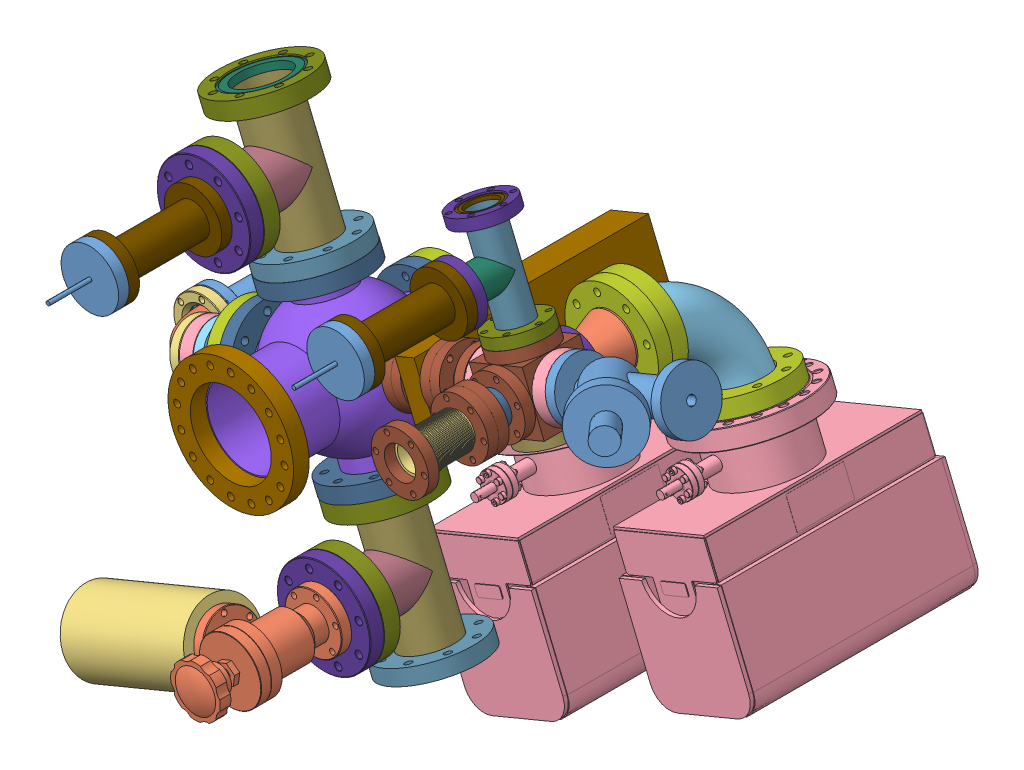
SolidWorks assembly Oven_BEC5, configuration Default. Lengths in mm.
Overall size (703.38 642.32 644.93).
104 component instances, 40 part files, 83 mates.
Components (placement in the parent):
- mdc 275 halfnipple-1: mdc 275 halfnipple [Default] at (-24.8274 -18.3346 25.5574) size (69.34 69.34 62.48)
- L275-403502-6: L275-403502 [Default] at (27.1869 1.5159 24.2874) x (-0.923728 -0.383049 0) z (0 0 -1) size (77.27 39.99 77.27)
- 915002-3: 915002 [Default] at (-24.8274 -18.3346 38.2574) x (0 0 -1) z (1 0 0) size (12.7 69.34 69.34)
- mdc 2.75 doublesided_hole-1: mdc 2.75 doublesided_hole [Default] at (43.4775 8.648 79.5644) x (0.146727 -0.353833 -0.923728) z (0.923728 0.383049 0) size (69.34 69.34 19.05)
- 915002-4: 915002 [Default] at (14.1491 -3.5138 79.5644) x (0.923728 0.383049 0) z (0 0 1) size (12.7 69.34 69.34)
- 100014 (2.75 X 1.5 REC)-1: 100014 (2.75 X 1.5 REC) [Default] at (43.4775 8.648 79.5644) x (0.923728 0.383049 0) z (0 0 1) size (12.7 69.34 69.34)
- red1-402032-001-1: red1-402032-001 [Default] at (97.817 31.1814 79.5644) x (-0.923728 -0.383049 0) z (0 0 1) size (60.1 63.5 63.5)
- 110021 (4.5 X 2.5 NR)-1: 110021 (4.5 X 2.5 NR) [Default] at (97.817 31.1814 79.5644) x (-0.923728 -0.383049 0) z (0 0 1) size (17.27 113.54 113.54)
- custom_sixway_cross-1: custom_sixway_cross [Default] at (189.7246 79.077 65.1716) x (-0.923728 -0.383049 0) z (-0.383049 0.923728 0) size (201.17 247.4 209.3)
  - custom_sixway_tube-1: custom_sixway_tube [Default] at (-1.4041 14.3928 -9.0374) size (170.94 210.82 174.24)
  - 6in_CF_flange-3: 6in_CF_flange [Default] at (-1.4041 157.1408 -9.0374) x (1 0 0) z (0 -1 0) size (152.4 152.4 19.05)
  - 4.5in_CF_flange-1: 4.5in_CF_flange [Default] at (85.7179 14.3928 -9.0374) x (0 -1 0) z (0 0 1) size (114.3 17.53 114.3)
  - 4.5in_CF_flange-2: 4.5in_CF_flange [Default] at (-1.4041 14.3928 78.0846) x (1 0 0) z (0 -1 0) size (114.3 17.53 114.3)
  - 4.5in_CF_flange-3: 4.5in_CF_flange [Default] at (-1.4041 14.3928 -113.6854) x (1 0 0) z (0 -1 0) size (114.3 17.53 114.3)
  - 2.75in_CF_flange-1: 2.75in_CF_flange [Default] at (-97.9241 14.3928 -9.0374) x (0 -1 0) z (0 0 1) size (69.85 12.7 69.85)
  - 4.5in_CF_flange-4: 4.5in_CF_flange [Default] at (-1.4041 -90.2552 -9.0374) size (114.3 17.53 114.3)
- T4-404038-1: T4-404038 [Default] at (92.3728 317.5077 79.5644) x (0.923728 0.383049 0) z (0.383049 -0.923728 0) size (113.54 142.49 171.45)
  - 404038-001-1: 404038-001 [Default] at origin size (63.51 63.51 152.4)
  - 404038-002-1: 404038-002 [Default] at (0 0 76.2) x (1 0 0) z (0 1 0) size (63.5 63.5 78.71)
  - 110021 (4.5 X 2.5 NR)_1-1: 110021 (4.5 X 2.5 NR)_1 [Default] at (0 0 161.925) x (0 0 -1) z (1 0 0) size (17.27 113.54 113.54)
  - 100021 (4.5 X 2.5 R)_1-1: 100021 (4.5 X 2.5 R)_1 [Default] at (0 73.025 76.2) x (0 1 0) z (0 0 1) size (19.05 113.54 113.54)
    - 100021 (4.5 X 2.5 INS)_1-1: 100021 (4.5 X 2.5 INS)_1 [Default] at origin size (12.04 82.3 82.3)
    - 100021 (4.5 X 2.5 REC)_1-1: 100021 (4.5 X 2.5 REC)_1 [Default] at (-6.35 0 0) x (1 0 0) z (0 0 -1) size (19.05 113.54 113.54)
  - 100021 (4.5 X 2.5 R)_1-2: 100021 (4.5 X 2.5 R)_1 [Default] at (0 0 3.175) x (0 0 -1) z (1 0 0) size (19.05 113.54 113.54)
    - 100021 (4.5 X 2.5 INS)_1-1: 100021 (4.5 X 2.5 INS)_1 [Default] at origin size (12.04 82.3 82.3)
    - 100021 (4.5 X 2.5 REC)_1-1: 100021 (4.5 X 2.5 REC)_1 [Default] at (-6.35 0 0) x (1 0 0) z (0 0 -1) size (19.05 113.54 113.54)
- zerolength 2.75 to 4.5 mdc-1: zerolength 2.75 to 4.5 mdc [Default] at (121.5611 247.1196 165.2894) x (-0.923728 -0.383049 0) z (0 0 -1) size (113.54 113.54 17.27)
- nipple 2.75 mdc-1: nipple 2.75 mdc [Default] at (121.5611 247.1196 307.7834) x (1 0 0) z (0 1 0) size (69.85 125.22 69.85)
- ion gauge uhv 24p footprint-1: ion gauge uhv 24p footprint [Default] at (121.5611 247.1196 320.4834) x (1 0 0) z (0 1 0) size (69.85 147.62 69.85)
- angle valve 1.5 inch 310029 mdc-1: angle valve 1.5 inch 310029 mdc [Default] at (267.4055 -104.5861 283.2724) x (-0.923728 -0.383049 0) z (-0.383049 0.923728 0) size (100.2 160.92 75.44)
- T4-404038-2: T4-404038 [Default] at (238.2172 -34.1981 79.5644) x (0.923728 0.383049 0) z (0.383049 -0.923728 0) size (113.54 142.49 171.45)
  - 404038-001-1: 404038-001 [Default] at origin size (63.51 63.51 152.4)
  - 404038-002-1: 404038-002 [Default] at (0 0 76.2) x (1 0 0) z (0 1 0) size (63.5 63.5 78.71)
  - 110021 (4.5 X 2.5 NR)_1-1: 110021 (4.5 X 2.5 NR)_1 [Default] at (0 0 161.925) x (0 0 -1) z (1 0 0) size (17.27 113.54 113.54)
  - 100021 (4.5 X 2.5 R)_1-1: 100021 (4.5 X 2.5 R)_1 [Default] at (0 73.025 76.2) x (0 1 0) z (0 0 1) size (19.05 113.54 113.54)
    - 100021 (4.5 X 2.5 INS)_1-1: 100021 (4.5 X 2.5 INS)_1 [Default] at origin size (12.04 82.3 82.3)
    - 100021 (4.5 X 2.5 REC)_1-1: 100021 (4.5 X 2.5 REC)_1 [Default] at (-6.35 0 0) x (1 0 0) z (0 0 -1) size (19.05 113.54 113.54)
  - 100021 (4.5 X 2.5 R)_1-2: 100021 (4.5 X 2.5 R)_1 [Default] at (0 0 3.175) x (0 0 -1) z (1 0 0) size (19.05 113.54 113.54)
    - 100021 (4.5 X 2.5 INS)_1-1: 100021 (4.5 X 2.5 INS)_1 [Default] at origin size (12.04 82.3 82.3)
    - 100021 (4.5 X 2.5 REC)_1-1: 100021 (4.5 X 2.5 REC)_1 [Default] at (-6.35 0 0) x (1 0 0) z (0 0 -1) size (19.05 113.54 113.54)
- zerolength 2.75 to 4.5 mdc-3: zerolength 2.75 to 4.5 mdc [Default] at (267.4055 -104.5861 165.2894) x (-0.923728 -0.383049 0) z (0 0 -1) size (113.54 113.54 17.27)
- turbo pump footpring-1: turbo pump footpring [Default] at (209.6873 -128.5206 245.9852) x (-0.383049 0.923728 0) z (0 0 1) size (91.44 162.05 91.44)
- ion pump gamma vacuum 75S-6S-KG_SW0003-1: ion pump gamma vacuum 75S-6S-KG_SW0003 [Default] at (324.7489 -242.8704 -129.9856) x (0.923728 0.383049 0) z (0 0 1) size (151.64 242.24 276.78)
- L4-403004_1-3: L4-403004_1 [Default] at (231.0174 -16.8357 -129.9856) x (0 0 1) z (-0.923728 -0.383049 0) size (161.67 161.67 113.54)
  - 403004-001_1-1: 403004-001_1 [Default] at origin size (128.92 128.92 67.08)
  - 100021 (4.5 X 2.5 R)_2-1: 100021 (4.5 X 2.5 R)_2 [Default] at (92.202 95.377 0) x (1 0 0) z (0 0 -1) size (19.05 113.54 113.54)
    - 100021 (4.5 X 2.5 INS)_2-1: 100021 (4.5 X 2.5 INS)_2 [Default] at origin size (12.04 82.3 82.3)
    - 100021 (4.5 X 2.5 REC)_2-1: 100021 (4.5 X 2.5 REC)_2 [Default] at (-6.35 0 0) x (1 0 0) z (0 0 -1) size (19.05 113.54 113.54)
  - 100021 (4.5 X 2.5 R)_2-2: 100021 (4.5 X 2.5 R)_2 [Default] at (0 3.175 0) x (0 -1 0) z (0 0 -1) size (19.05 113.54 113.54)
    - 100021 (4.5 X 2.5 INS)_2-1: 100021 (4.5 X 2.5 INS)_2 [Default] at origin size (12.04 82.3 82.3)
    - 100021 (4.5 X 2.5 REC)_2-1: 100021 (4.5 X 2.5 REC)_2 [Default] at (-6.35 0 0) x (1 0 0) z (0 0 -1) size (19.05 113.54 113.54)
- zerolength 6 45 mdc-1: zerolength 6 45 mdc [Default] at (242.2549 -43.9351 -129.9856) x (0.853273 0.353833 -0.383049) z (0.383049 -0.923728 0) size (151.64 151.64 19.81)
- gatevalve-1: gatevalve [Default] at (298.9549 11.514 55.3656) x (0.383049 -0.923728 0) z (0.923728 0.383049 0) size (88.9 280.54 50.84)
  - gatevalve_body-1: gatevalve_body [Default] at (-95.213 2.8522 48.3049) size (88.9 277.88 50.04)
  - 2.75in_CF_flange-3: 2.75in_CF_flange [Default] at (-95.213 -24.1988 73.7492) x (1 0 0) z (0 1 0) size (69.85 12.7 69.85)
  - 2.75in_CF_flange-4: 2.75in_CF_flange [Default] at (-95.213 -24.1988 35.6049) x (-1 0 0) z (0 -1 0) size (69.85 12.7 69.85)
- minilength_nipple-1: minilength_nipple [Default] at (349.6703 127.2966 78.7528) x (0.383049 -0.923728 0) z (0 0 1) size (69.85 44.45 69.85)
  - minilength_nipple_tube-1: minilength_nipple_tube [Default] at (-7.6879 4.7765 0.8117) size (38.1 19.05 38.1)
  - 2.75in_CF_flange-3: 2.75in_CF_flange [Default] at (-7.6879 14.3015 0.8117) size (69.85 12.7 69.85)
  - 2.75in_CF_flange-4: 2.75in_CF_flange [Default] at (-7.6879 -17.4485 0.8117) size (69.85 12.7 69.85)
- mdc 2.75 doublesided_hole-4: mdc 2.75 doublesided_hole [Default] at (371.6676 144.741 79.5644) x (0.146727 -0.353833 0.923728) z (-0.923728 -0.383049 0) size (69.34 69.34 19.05)
- mdc 2.75 doublesided_hole-5: mdc 2.75 doublesided_hole [Default] at (453.787 178.7941 79.5644) x (0.146727 -0.353833 0.923728) z (-0.923728 -0.383049 0) size (69.34 69.34 19.05)
- six way cube-1: six way cube [Default] at (421.5258 165.4161 79.5644) x (0 0 1) z (-0.923728 -0.383049 0) size (69.85 69.85 69.85)
- 2.75in  window mdc-1: 2.75in  window mdc [Default] at (439.7685 121.4235 79.5644) x (0.853273 0.353833 0.383049) z (-0.383049 0.923728 0) size (69.34 69.34 12.7)
  - Part3^2.75in  window mdc-1: Part3^2.75in  window mdc [Default] at origin size (69.34 69.34 12.7) (virtual)
  - Part4^2.75in  window mdc-1: Part4^2.75in  window mdc [Default] at (0 0 12.7) size (38.1 38.1 2.67) (virtual)
- T275-404002_a-1: T275-404002_a [Default] at (357.4671 319.8944 79.5644) x (0.923728 0.383049 0) z (0.383049 -0.923728 0) size (69.34 97.13 124.92)
  - 404002-001-1: 404002-001 [Default] at origin size (38.1 38.1 114.3)
  - 404002-002-1: 404002-002 [Default] at (0 0 57.15) x (-1 0 0) z (0 1 0) size (38.1 38.1 58.53)
  - 110014 (2.75 X 1.5 NR)_1-1: 110014 (2.75 X 1.5 NR)_1 [Default] at (0 0 113.2586) x (0 0 1) z (-1 0 0) size (12.7 69.34 69.34)
  - 100014 (2.75 X 1.5 R)-1: 100014 (2.75 X 1.5 R) [Default] at (0 62.4586 57.15) x (0 -1 0) z (1 0 0) size (12.7 69.34 69.34)
    - 100014 (2.75 X 1.5 REC)_1-1: 100014 (2.75 X 1.5 REC)_1 [Default] at origin size (12.7 69.34 69.34)
    - 100014 (2.75 X 1.5 INS)-1: 100014 (2.75 X 1.5 INS) [Default] at (1.17 0 0) x (1 0 0) z (0 0.994423 -0.105464) size (6.96 48.1 48.1)
  - 100014 (2.75 X 1.5 R)-2: 100014 (2.75 X 1.5 R) [Default] at (0 0 -5.3086) x (0 0 1) z (-1 0 0) size (12.7 69.34 69.34)
    - 100014 (2.75 X 1.5 REC)_1-1: 100014 (2.75 X 1.5 REC)_1 [Default] at origin size (12.7 69.34 69.34)
    - 100014 (2.75 X 1.5 INS)-1: 100014 (2.75 X 1.5 INS) [Default] at (1.17 0 0) x (1 0 0) z (0 0.994423 -0.105464) size (6.96 48.1 48.1)
- 2.75in_CF_flange-1: 2.75in_CF_flange [Default] at (403.2831 209.4086 79.5644) x (-0.923728 -0.383049 0) z (0 0 1) size (69.85 12.7 69.85)
- nipple 2.75 mdc-2: nipple 2.75 mdc [Default] at (379.3584 267.1034 142.023) x (1 0 0) z (0 -1 0) size (69.85 125.22 69.85)
- ion gauge uhv 24p footprint-2: ion gauge uhv 24p footprint [Default] at (379.3584 267.1034 279.945) x (1 0 0) z (0 1 0) size (69.85 147.62 69.85)
- valve mdc inline all metal small-1: valve mdc inline all metal small [Default] at (470.2109 185.6047 79.5644) x (-0.383049 0.923728 0) z (0 0 -1) size (75.44 172.37 161.4)
- 402032-1: 402032 [Default] at (421.5258 165.4161 -20.7656) x (0 0 1) z (-1 0 0) size (74.93 113.54 113.54)
  - 402032-001-1: 402032-001 [Default] at origin size (60.1 63.5 63.5)
  - 110021 (4.5 X 2.5 NR)-1: 110021 (4.5 X 2.5 NR) [Default] at (-9.525 0 0) size (17.27 113.54 113.54)
  - 100014 (2.75 X 1.5 R)-1: 100014 (2.75 X 1.5 R) [Default] at (65.405 0 0) x (-1 0 0) z (0 0 -1) size (12.7 69.34 69.34)
    - 100014 (2.75 X 1.5 REC)_1-1: 100014 (2.75 X 1.5 REC)_1 [Default] at origin size (12.7 69.34 69.34)
    - 100014 (2.75 X 1.5 INS)-1: 100014 (2.75 X 1.5 INS) [Default] at (1.17 0 0) x (1 0 0) z (0 0.994423 -0.105464) size (6.96 48.1 48.1)
- L4-403004_1-4: L4-403004_1 [Default] at (421.5258 165.4161 -39.8156) x (0.383049 -0.923728 0) z (0.923728 0.383049 0) size (161.67 161.67 113.54)
  - 403004-001_1-1: 403004-001_1 [Default] at origin size (128.92 128.92 67.08)
  - 100021 (4.5 X 2.5 R)_2-1: 100021 (4.5 X 2.5 R)_2 [Default] at (92.202 95.377 0) x (1 0 0) z (0 0 -1) size (19.05 113.54 113.54)
    - 100021 (4.5 X 2.5 INS)_2-1: 100021 (4.5 X 2.5 INS)_2 [Default] at origin size (12.04 82.3 82.3)
    - 100021 (4.5 X 2.5 REC)_2-1: 100021 (4.5 X 2.5 REC)_2 [Default] at (-6.35 0 0) x (1 0 0) z (0 0 -1) size (19.05 113.54 113.54)
  - 100021 (4.5 X 2.5 R)_2-2: 100021 (4.5 X 2.5 R)_2 [Default] at (0 3.175 0) x (0 -1 0) z (0 0 -1) size (19.05 113.54 113.54)
    - 100021 (4.5 X 2.5 INS)_2-1: 100021 (4.5 X 2.5 INS)_2 [Default] at origin size (12.04 82.3 82.3)
    - 100021 (4.5 X 2.5 REC)_2-1: 100021 (4.5 X 2.5 REC)_2 [Default] at (-6.35 0 0) x (1 0 0) z (0 0 -1) size (19.05 113.54 113.54)
- ion pump gamma vacuum 75S-6S-KG_SW0003-2: ion pump gamma vacuum 75S-6S-KG_SW0003 [Default] at (545.1364 -132.6726 -135.1926) x (0.923728 0.383049 0) z (0 0 1) size (151.64 242.24 276.78)
- minilength_nipple-2: minilength_nipple [Default] at (429.2137 166.2277 131.9379) x (1 0 0) z (0 -1 0) size (69.85 44.45 69.85)
  - minilength_nipple_tube-1: minilength_nipple_tube [Default] at (-7.6879 4.7765 0.8117) size (38.1 19.05 38.1)
  - 2.75in_CF_flange-3: 2.75in_CF_flange [Default] at (-7.6879 14.3015 0.8117) size (69.85 12.7 69.85)
  - 2.75in_CF_flange-4: 2.75in_CF_flange [Default] at (-7.6879 -17.4485 0.8117) size (69.85 12.7 69.85)
- Bellow_2.75in_CF-1: Bellow_2.75in_CF [Default] at (449.3378 155.3944 206.3015) x (1 0 0) z (0 1 0) size (96.68 84.96 96.68)
  - 2.75in_bellow_tube-1: 2.75in_bellow_tube [Default] at (-27.8121 6.8508 10.0217) size (43.18 63.5 43.18)
  - 2.75in_CF_flange-1: 2.75in_CF_flange [Default] at (-27.8121 47.3621 10.0217) x (-0.837169 0 -0.546944) z (-0.546944 0 0.837169) size (69.85 12.7 69.85)
  - 2.75in_CF_flange-2: 2.75in_CF_flange [Default] at (-27.8121 -24.8992 10.0217) x (-0.837169 0 -0.546944) z (-0.546944 0 0.837169) size (69.85 12.7 69.85)
- 404002-001_1-1: 404002-001_1 [Default] at (115.1337 -161.6135 43.2434)
Mates (geometry in assembly coordinates):
- Coincident9: coincident anti-aligned: plane of mdc 275 halfnipple-1 through (-24.8274 -18.3346 24.2874) normal (0 0 1); plane of L275-403502-6 through (-25.6042 -20.3753 24.2874) normal (0 0 -1)
- Tangent4: tangent: cylinder of mdc 275 halfnipple-1 through (-24.8274 -18.3346 24.2874) axis (0 0 -1) radius 17.4625; face of L275-403502-6
- Coincident12: coincident anti-aligned: plane of mdc 275 halfnipple-1 through (-24.8274 -18.3346 25.5574) normal (0 0 1); plane of 915002-3 through (-24.8274 -18.3346 25.5574) normal (0 0 -1)
- Coincident14: coincident anti-aligned: plane of mdc 275 halfnipple-1 through (-24.8274 -18.3346 25.5574) normal (0 0 1); plane of 915002-3 through (-24.8274 -18.3346 25.5574) normal (0 0 -1)
- Coincident15: coincident aligned: circle of mdc 275 halfnipple-1; circle of 915002-3
- Coincident16: coincident anti-aligned: plane of L275-403502-6 through (27.1869 1.5159 81.4374) normal (0.923728 0.383049 0); plane of mdc 2.75 doublesided_hole-1 through (27.0536 1.8374 79.5644) normal (-0.923728 -0.383049 0)
- Tangent6: tangent: face of L275-403502-6; cylinder of mdc 2.75 doublesided_hole-1 through (27.6508 2.0851 79.5644) axis (0.923728 0.383049 0) radius 20.955
- Coincident17: coincident anti-aligned: plane of mdc 2.75 doublesided_hole-1 through (25.8804 1.3509 79.5644) normal (-0.923728 -0.383049 0); plane of 915002-4 through (25.8804 1.3509 79.5644) normal (0.923728 0.383049 0)
- Coincident18: coincident anti-aligned: circle of 915002-4; circle of mdc 2.75 doublesided_hole-1
- Coincident19: coincident anti-aligned: plane of mdc 2.75 doublesided_hole-1 through (42.3043 8.1616 79.5644) normal (0.923728 0.383049 0); plane of red1-402032-001-1 through (49.2852 -8.6729 79.5644) normal (-0.923728 -0.383049 0)
- Concentric1: concentric anti-aligned: cylinder of mdc 2.75 doublesided_hole-1 through (41.7071 7.9139 79.5644) axis (0.923728 0.383049 0) radius 20.955; cylinder of red1-402032-001-1 through (48.17 10.5939 79.5644) axis (-0.923728 -0.383049 0) radius 19.05
- Coincident20: coincident anti-aligned: plane of mdc 2.75 doublesided_hole-1 through (43.4775 8.648 79.5644) normal (0.923728 0.383049 0); plane of 100014 (2.75 X 1.5 REC)-1 through (32.2261 35.7809 79.5644) normal (-0.923728 -0.383049 0)
- Concentric2: concentric anti-aligned: cylinder of 100014 (2.75 X 1.5 REC)-1 through (46.9969 10.1074 79.5644) axis (0.923728 0.383049 0) radius 24.0754; cylinder of red1-402032-001-1 through (48.17 10.5939 79.5644) axis (-0.923728 -0.383049 0) radius 19.05
- Coincident22: coincident anti-aligned: plane of red1-402032-001-1 through (109.6626 2.6156 79.5644) normal (0.923728 0.383049 0); plane of custom_sixway_cross-1/4.5in_CF_flange-1 through (97.817 31.1814 79.5644) normal (-0.923728 -0.383049 0)
- Coincident23: coincident aligned: circle of red1-402032-001-1; circle of custom_sixway_cross-1/4.5in_CF_flange-1
- Coincident24: coincident anti-aligned: plane of 110021 (4.5 X 2.5 NR)-1 through (116.5949 -14.1016 79.5644) normal (0.923728 0.383049 0); plane of custom_sixway_cross-1/4.5in_CF_flange-1 through (97.817 31.1814 79.5644) normal (-0.923728 -0.383049 0)
- Concentric3: concentric aligned: cylinder of red1-402032-001-1 through (93.4178 29.3571 79.5644) axis (-0.923728 -0.383049 0) radius 31.75; cylinder of 110021 (4.5 X 2.5 NR)-1 through (92.8774 29.1331 79.5644) axis (-0.923728 -0.383049 0) radius 30.1625
- Parallel6: parallel aligned: plane of mdc 275 halfnipple-1 through (-24.8274 -18.3346 -36.9266) normal (0 0 -1); plane of custom_sixway_cross-1/4.5in_CF_flange-4 through (194.4833 71.2667 -25.0836) normal (0 0 -1)
- Coincident26: coincident anti-aligned: plane of custom_sixway_cross-1/4.5in_CF_flange-2 through (154.398 167.933 79.5644) normal (-0.383049 0.923728 0); plane of T4-404038-1/110021 (4.5 X 2.5 NR)_1-1 through (154.398 167.933 128.5864) normal (0.383049 -0.923728 0)
- Concentric4: concentric aligned: circle of custom_sixway_cross-1/4.5in_CF_flange-2; circle of T4-404038-1/110021 (4.5 X 2.5 NR)_1-1
- Parallel7: parallel aligned: plane of custom_sixway_cross-1/6in_CF_flange-3 through (194.4833 71.2667 222.3124) normal (0 0 1); plane of T4-404038-1/100021 (4.5 X 2.5 R)_1-1/100021 (4.5 X 2.5 REC)_1-1 through (166.8441 265.8974 165.2894) normal (0 0 1)
- Coincident28: coincident anti-aligned: plane of T4-404038-1/100021 (4.5 X 2.5 R)_1-1/100021 (4.5 X 2.5 REC)_1-1 through (166.8441 265.8974 165.2894) normal (0 0 1); plane of zerolength 2.75 to 4.5 mdc-1 through (121.5611 247.1196 165.2894) normal (0 0 -1)
- Concentric5: concentric aligned: circle of T4-404038-1/100021 (4.5 X 2.5 R)_1-1/100021 (4.5 X 2.5 INS)_1-1; circle of zerolength 2.75 to 4.5 mdc-1
- Coincident29: coincident anti-aligned: plane of zerolength 2.75 to 4.5 mdc-1 through (121.5611 247.1196 182.5614) normal (0 0 1); plane of nipple 2.75 mdc-1 through (121.5611 247.1196 182.5614) normal (0 0 -1)
- Concentric6: concentric aligned: circle of zerolength 2.75 to 4.5 mdc-1; circle of nipple 2.75 mdc-1
- Coincident30: coincident anti-aligned: plane of nipple 2.75 mdc-1 through (121.5611 247.1196 307.7834) normal (0 0 1); plane of ion gauge uhv 24p footprint-1 through (121.5611 247.1196 307.7834) normal (0 0 -1)
- Concentric7: concentric aligned: cylinder of nipple 2.75 mdc-1 through (121.5611 247.1196 182.5614) axis (0 0 1) radius 17.526; cylinder of ion gauge uhv 24p footprint-1 through (121.5611 247.1196 223.6586) axis (0 0 1) radius 16.637
- Coincident33: coincident anti-aligned: plane of custom_sixway_cross-1/4.5in_CF_flange-3 through (234.5687 -25.3996 79.5644) normal (0.383049 -0.923728 0); plane of T4-404038-2/100021 (4.5 X 2.5 R)_1-2/100021 (4.5 X 2.5 REC)_1-1 through (234.5687 -25.3996 30.5424) normal (-0.383049 0.923728 0)
- Concentric9: concentric anti-aligned: circle of custom_sixway_cross-1/4.5in_CF_flange-3; circle of T4-404038-2/100021 (4.5 X 2.5 R)_1-2/100021 (4.5 X 2.5 INS)_1-1
- Parallel8: parallel aligned: plane of custom_sixway_cross-1/6in_CF_flange-3 through (194.4833 71.2667 222.3124) normal (0 0 1); plane of T4-404038-2/100021 (4.5 X 2.5 R)_1-1/100021 (4.5 X 2.5 REC)_1-1 through (312.6885 -85.8083 165.2894) normal (0 0 1)
- Coincident35: coincident anti-aligned: plane of T4-404038-2/100021 (4.5 X 2.5 R)_1-1/100021 (4.5 X 2.5 REC)_1-1 through (312.6885 -85.8083 165.2894) normal (0 0 1); plane of zerolength 2.75 to 4.5 mdc-3 through (267.4055 -104.5861 165.2894) normal (0 0 -1)
- Concentric10: concentric aligned: circle of T4-404038-2/100021 (4.5 X 2.5 R)_1-1/100021 (4.5 X 2.5 INS)_1-1; circle of zerolength 2.75 to 4.5 mdc-3
- Coincident36: coincident anti-aligned: plane of angle valve 1.5 inch 310029 mdc-1 through (267.4055 -104.5861 182.5614) normal (0 0 -1); plane of zerolength 2.75 to 4.5 mdc-3 through (267.4055 -104.5861 182.5614) normal (0 0 1)
- Concentric11: concentric anti-aligned: circle of angle valve 1.5 inch 310029 mdc-1; circle of zerolength 2.75 to 4.5 mdc-3
- Parallel9: parallel anti-aligned: plane of angle valve 1.5 inch 310029 mdc-1 through (209.6873 -128.5206 245.9852) normal (-0.923728 -0.383049 0); plane of custom_sixway_cross-1/4.5in_CF_flange-1 through (114.0063 37.8947 79.5644) normal (0.923728 0.383049 0)
- Coincident38: coincident anti-aligned: plane of angle valve 1.5 inch 310029 mdc-1 through (209.6873 -128.5206 245.9852) normal (-0.923728 -0.383049 0); plane of turbo pump footpring-1 through (209.6873 -128.5206 245.9852) normal (0.923728 0.383049 0)
- Concentric12: concentric aligned: circle of angle valve 1.5 inch 310029 mdc-1; circle of turbo pump footpring-1
- Coincident43: coincident anti-aligned: plane of custom_sixway_cross-1/4.5in_CF_flange-4 through (194.4833 71.2667 -25.0836) normal (0 0 -1); plane of L4-403004_1-3/100021 (4.5 X 2.5 R)_2-1/100021 (4.5 X 2.5 REC)_2-1 through (175.7055 116.5497 -25.0836) normal (0 0 1)
- Concentric14: concentric anti-aligned: circle of custom_sixway_cross-1/4.5in_CF_flange-4; circle of L4-403004_1-3/100021 (4.5 X 2.5 R)_2-1/100021 (4.5 X 2.5 INS)_2-1
- Parallel11: parallel aligned: plane of T4-404038-2/110021 (4.5 X 2.5 NR)_1-1 through (300.2424 -183.7727 128.5864) normal (0.383049 -0.923728 0); plane of L4-403004_1-3/100021 (4.5 X 2.5 R)_2-2/100021 (4.5 X 2.5 REC)_2-1 through (234.6659 -25.6342 -80.9636) normal (0.383049 -0.923728 0)
- Coincident45: coincident anti-aligned: plane of L4-403004_1-3/100021 (4.5 X 2.5 R)_2-2/100021 (4.5 X 2.5 REC)_2-1 through (234.6659 -25.6342 -80.9636) normal (0.383049 -0.923728 0); plane of zerolength 6 45 mdc-1 through (234.6659 -25.6342 -129.9856) normal (-0.383049 0.923728 0)
- Concentric15: concentric aligned: circle of L4-403004_1-3/100021 (4.5 X 2.5 R)_2-2/100021 (4.5 X 2.5 INS)_2-1; circle of zerolength 6 45 mdc-1
- Coincident46: coincident anti-aligned: plane of ion pump gamma vacuum 75S-6S-KG_SW0003-1 through (241.7684 -42.7619 -129.9856) normal (-0.383049 0.923728 0); plane of zerolength 6 45 mdc-1 through (241.7684 -42.7619 -129.9856) normal (0.383049 -0.923728 0)
- Concentric16: concentric anti-aligned: circle of ion pump gamma vacuum 75S-6S-KG_SW0003-1; circle of zerolength 6 45 mdc-1
- Parallel12: parallel aligned: plane of T4-404038-2/110021 (4.5 X 2.5 NR)_1-1 through (300.2424 -183.7727 128.5864) normal (0.383049 -0.923728 0); plane of ion pump gamma vacuum 75S-6S-KG_SW0003-1 through (297.2543 -280.47 -263.4856) normal (0.383049 -0.923728 0)
- Coincident48: coincident anti-aligned: plane of custom_sixway_cross-1/2.75in_CF_flange-1 through (283.6416 108.2386 79.5644) normal (0.923728 0.383049 0); plane of gatevalve-1/2.75in_CF_flange-4 through (283.6416 108.2386 79.5644) normal (-0.923728 -0.383049 0)
- Coincident49: coincident aligned: circle of custom_sixway_cross-1/2.75in_CF_flange-1; circle of gatevalve-1/2.75in_CF_flange-4
- Parallel13: parallel aligned: plane of ion pump gamma vacuum 75S-6S-KG_SW0003-1 through (285.1991 -147.4955 -262.9356) normal (0 0 -1); plane of gatevalve-1/gatevalve_body-1 through (301.02 67.3249 -166.0536) normal (0 0 -1)
- Coincident51: coincident anti-aligned: plane of gatevalve-1/2.75in_CF_flange-3 through (330.6079 127.7145 79.5644) normal (0.923728 0.383049 0); plane of minilength_nipple-1/2.75in_CF_flange-4 through (330.6079 127.7145 79.5644) normal (-0.923728 -0.383049 0)
- Coincident52: coincident anti-aligned: circle of gatevalve-1/2.75in_CF_flange-3; circle of minilength_nipple-1/2.75in_CF_flange-4
- Coincident53: coincident anti-aligned: plane of minilength_nipple-1/2.75in_CF_flange-3 through (371.6676 144.741 79.5644) normal (0.923728 0.383049 0); plane of mdc 2.75 doublesided_hole-4 through (371.6676 144.741 79.5644) normal (-0.923728 -0.383049 0)
- Concentric17: concentric aligned: circle of minilength_nipple-1/2.75in_CF_flange-3; circle of mdc 2.75 doublesided_hole-4
- Coincident54: coincident anti-aligned: plane of mdc 2.75 doublesided_hole-4 through (389.2646 152.0381 79.5644) normal (0.923728 0.383049 0); plane of six way cube-1 through (375.8866 184.2993 44.6394) normal (-0.923728 -0.383049 0)
- Concentric18: concentric anti-aligned: circle of mdc 2.75 doublesided_hole-4; circle of six way cube-1
- Parallel14: parallel aligned: plane of custom_sixway_cross-1/6in_CF_flange-3 through (194.4833 71.2667 222.3124) normal (0 0 1); plane of six way cube-1 through (402.6426 119.7769 114.4894) normal (0 0 1)
- Coincident56: coincident anti-aligned: plane of mdc 2.75 doublesided_hole-5 through (453.787 178.7941 79.5644) normal (-0.923728 -0.383049 0); plane of six way cube-1 through (440.409 211.0553 44.6394) normal (0.923728 0.383049 0)
- Coincident57: coincident aligned: circle of mdc 2.75 doublesided_hole-5; circle of six way cube-1
- Coincident58: coincident anti-aligned: plane of six way cube-1 through (402.6426 119.7769 44.6394) normal (0.383049 -0.923728 0); plane of 2.75in  window mdc-1/Part3^2.75in  window mdc-1 through (434.9038 133.1549 79.5644) normal (-0.383049 0.923728 0)
- Concentric19: concentric aligned: circle of six way cube-1; circle of 2.75in  window mdc-1/Part3^2.75in  window mdc-1
- Coincident59: coincident anti-aligned: plane of six way cube-1 through (375.8866 184.2993 44.6394) normal (-0.383049 0.923728 0); plane of 2.75in_CF_flange-1 through (408.1478 197.6773 79.5644) normal (0.383049 -0.923728 0)
- Concentric20: concentric anti-aligned: circle of six way cube-1; circle of 2.75in_CF_flange-1
- Coincident60: coincident anti-aligned: plane of T275-404002_a-1/110014 (2.75 X 1.5 NR)_1-1 through (403.2831 209.4086 50.1539) normal (0.383049 -0.923728 0); plane of 2.75in_CF_flange-1 through (403.2831 209.4086 79.5644) normal (-0.383049 0.923728 0)
- Concentric21: concentric anti-aligned: circle of T275-404002_a-1/110014 (2.75 X 1.5 NR)_1-1; circle of 2.75in_CF_flange-1
- Parallel15: parallel: plane of six way cube-1 through (402.6426 119.7769 114.4894) normal (0 0 1); plane of T275-404002_a-1/100014 (2.75 X 1.5 R)-1/100014 (2.75 X 1.5 REC)_1-1 through (368.107 294.2362 142.023) normal (0 0 1)
- Coincident62: coincident: plane of T275-404002_a-1/100014 (2.75 X 1.5 R)-1/100014 (2.75 X 1.5 REC)_1-1 through (368.107 294.2362 142.023) normal (0 0 1); plane of nipple 2.75 mdc-2 through (379.3584 267.1034 142.023) normal (0 0 -1)
- Concentric22: concentric: circle of T275-404002_a-1/100014 (2.75 X 1.5 R)-1/100014 (2.75 X 1.5 REC)_1-1; circle of nipple 2.75 mdc-2
- Coincident63: coincident anti-aligned: plane of nipple 2.75 mdc-2 through (379.3584 267.1034 267.245) normal (0 0 1); plane of ion gauge uhv 24p footprint-2 through (379.3584 267.1034 267.245) normal (0 0 -1)
- Concentric23: concentric anti-aligned: cylinder of nipple 2.75 mdc-2 through (379.3584 267.1034 267.245) axis (0 0 -1) radius 17.526; cylinder of ion gauge uhv 24p footprint-2 through (379.3584 267.1034 183.1202) axis (0 0 1) radius 16.637
- Coincident65: coincident anti-aligned: plane of mdc 2.75 doublesided_hole-5 through (470.2109 185.6047 79.5644) normal (0.923728 0.383049 0); plane of valve mdc inline all metal small-1 through (470.2109 185.6047 79.5644) normal (-0.923728 -0.383049 0)
- Concentric25: concentric aligned: circle of mdc 2.75 doublesided_hole-5; circle of valve mdc inline all metal small-1
- Angle1: planar angle = 0.785398 rad aligned: plane of valve mdc inline all metal small-1 through (593.8073 236.8573 167.8974) normal (0.653174 0.270857 0.707107); plane of nipple 2.75 mdc-2 through (379.3584 267.1034 154.723) normal (0 0 1)
- Coincident67: coincident: plane of six way cube-1 through (402.6426 119.7769 44.6394) normal (0 0 -1); plane of 402032-1/100014 (2.75 X 1.5 R)-1/100014 (2.75 X 1.5 REC)_1-1 through (421.5258 194.7893 44.6394) normal (0 0 1)
- Concentric26: concentric: circle of six way cube-1; circle of 402032-1/100014 (2.75 X 1.5 R)-1/100014 (2.75 X 1.5 REC)_1-1
- Coincident68: coincident anti-aligned: plane of 402032-1/110021 (4.5 X 2.5 NR)-1 through (421.5258 214.4381 -30.2906) normal (0 0 -1); plane of L4-403004_1-4/100021 (4.5 X 2.5 R)_2-2/100021 (4.5 X 2.5 REC)_2-1 through (440.3036 120.1331 -30.2906) normal (0 0 1)
- Concentric27: concentric anti-aligned: circle of 402032-1/110021 (4.5 X 2.5 NR)-1; circle of L4-403004_1-4/100021 (4.5 X 2.5 R)_2-2/100021 (4.5 X 2.5 REC)_2-1
- Parallel16: parallel aligned: plane of 2.75in  window mdc-1/Part3^2.75in  window mdc-1 through (439.7685 121.4235 79.5644) normal (0.383049 -0.923728 0); plane of L4-403004_1-4/100021 (4.5 X 2.5 R)_2-1/100021 (4.5 X 2.5 REC)_2-1 through (461.7084 68.5152 -184.2146) normal (0.383049 -0.923728 0)
- Coincident70: coincident anti-aligned: plane of L4-403004_1-4/100021 (4.5 X 2.5 R)_2-1/100021 (4.5 X 2.5 REC)_2-1 through (461.7084 68.5152 -184.2146) normal (0.383049 -0.923728 0); plane of ion pump gamma vacuum 75S-6S-KG_SW0003-2 through (461.7084 68.5152 -135.1926) normal (-0.383049 0.923728 0)
- Concentric28: concentric anti-aligned: circle of L4-403004_1-4/100021 (4.5 X 2.5 R)_2-1/100021 (4.5 X 2.5 REC)_2-1; circle of ion pump gamma vacuum 75S-6S-KG_SW0003-2
- Parallel17: parallel aligned: plane of ion pump gamma vacuum 75S-6S-KG_SW0003-1 through (345.3158 -124.0821 8.3404) normal (0 0 1); plane of ion pump gamma vacuum 75S-6S-KG_SW0003-2 through (565.7033 -13.8843 3.1334) normal (0 0 1)
- Coincident72: coincident anti-aligned: plane of six way cube-1 through (402.6426 119.7769 114.4894) normal (0 0 1); plane of minilength_nipple-2/2.75in_CF_flange-4 through (421.5258 165.4161 114.4894) normal (0 0 -1)
- Concentric29: concentric aligned: circle of six way cube-1; circle of minilength_nipple-2/2.75in_CF_flange-4
- Coincident74: coincident anti-aligned: plane of minilength_nipple-2/2.75in_CF_flange-3 through (421.5258 165.4161 158.9394) normal (0 0 1); plane of Bellow_2.75in_CF-1/2.75in_CF_flange-1 through (421.5258 165.4161 158.9394) normal (0 0 -1)
- Coincident75: coincident aligned: circle of minilength_nipple-2/2.75in_CF_flange-3; circle of Bellow_2.75in_CF-1/2.75in_CF_flange-1
